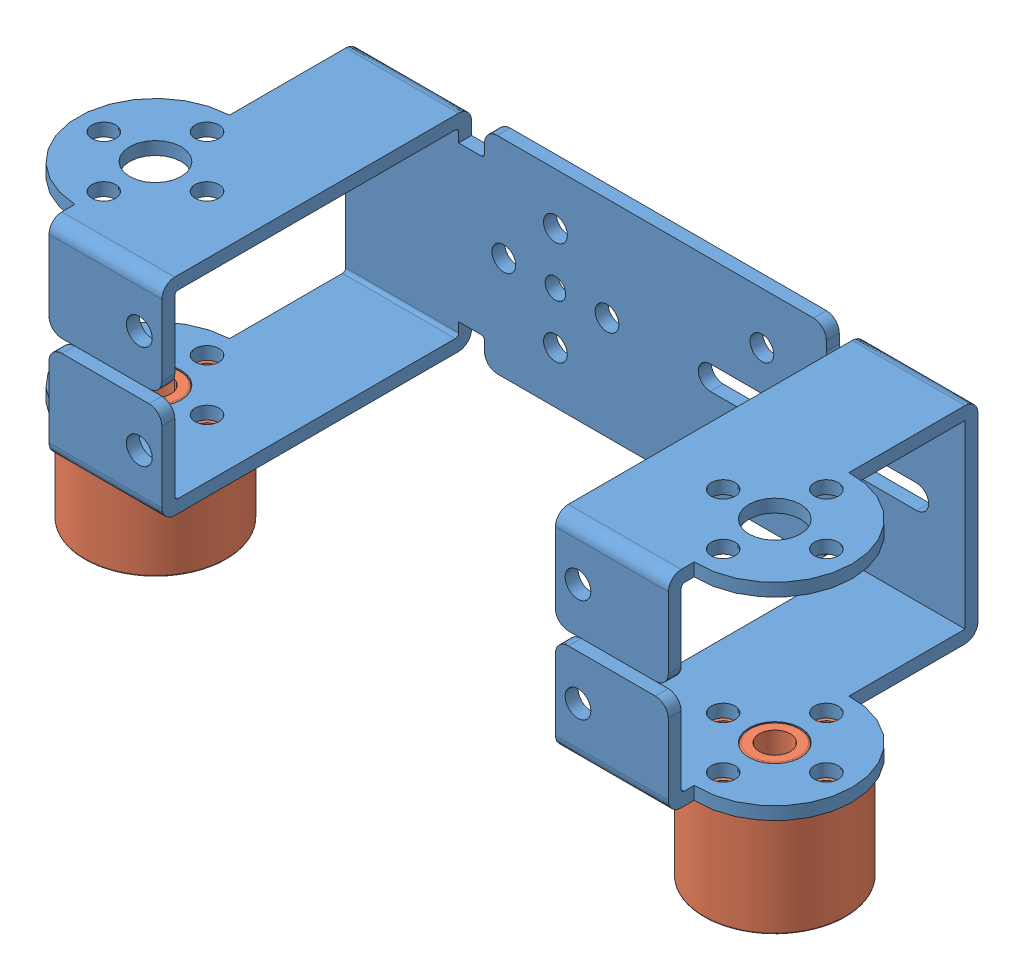
SolidWorks assembly Example Servo Mount, configuration Default. Lengths in mm.
Overall size (120 50 48).
3 component instances, 2 part files, 0 mates.
Components (placement in the parent):
- Tetrix Servo Large Bracket-1: Tetrix Servo Large Bracket [Default] at origin size (120 32 48)
- Tetrix Servo Spacer-1: Tetrix Servo Spacer [Default] at (-47.5 -24 32) size (22 20 22)
- Tetrix Servo Spacer-2: Tetrix Servo Spacer [Default] at (48.5 -24 32) size (22 20 22)
